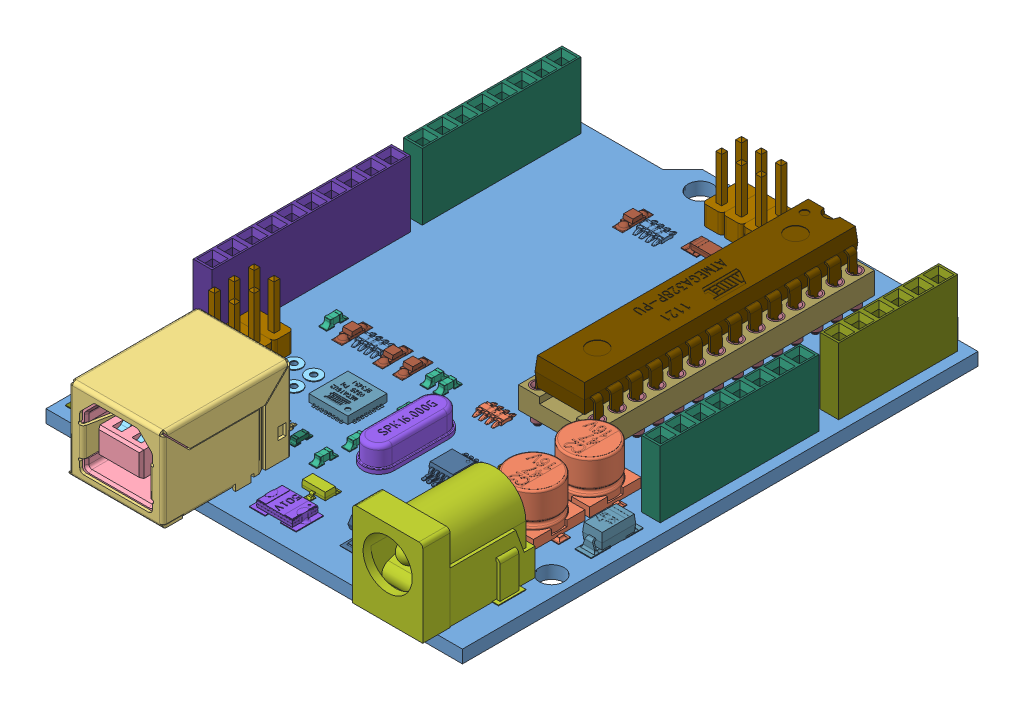
SolidWorks assembly arduino uno, configuration Default. Lengths in mm.
Overall size (53.34 15.25 74.97).
87 component instances, 35 part files, 133 mates.
Components (placement in the parent):
- unoboard blue-1: unoboard blue [Default] at origin size (53.34 1.65 68.58)
- 47uf CAP Dcase-1: 47uf CAP Dcase [Default] at (-9.4141 0 -18.4991) x (0 0 -1) z (1 0 0) size (6.6 5.81 8)
- USB type b-1: USB type b [Default] at (-38.02 0.43 6.35) size (14.34 15.2 16.54)
  - USB SHELL-1: USB SHELL [Default] at origin size (14.34 15.2 16.54)
  - USB core-1: USB core [Default] at origin size (11.3 10.68 15.75)
  - usb top contact-1: usb top contact [Default] at (1.25 6.09 -0.38) size (1 9.67 13.76)
  - usb btm contact-1: usb btm contact [Default] at (1.25 4.41 -0.38) size (1 6.84 11.76)
  - usb btm contact-2: usb btm contact [Default] at (-1.25 4.41 -0.38) size (1 6.84 11.76)
  - usb top contact-2: usb top contact [Default] at (-1.25 6.09 -0.38) size (1 9.67 13.76)
- power jack-1: power jack [Default] at (-7.675 0 1.905) size (11.2 15.2 15.9)
- 47uf CAP Dcase-2: 47uf CAP Dcase [Default] at (-9.4141 0 -25.7132) x (0 0 -1) z (1 0 0) size (6.6 5.81 8)
- crystal-1: crystal [Default] at (-26.162 0 -18.923) x (1 0 0) z (0 0 -1) size (4 5 11)
- 2pin_header__02-1: 2pin_header__02 [Default] at (-46.23 0 -15.75) size (5 11.75 2.54)
- nano - reg-1: nano - reg [Default] at (-17.399 0 -7.747) size (6.5 1.69 8.3)
- led-1: led [Default] at (-34.29 0 -27.94) x (0 0 1) z (-1 0 0) size (4 0.86 1.35)
- 2pin_header__02-2: 2pin_header__02 [Default] at (-30.43 0 -64.91) x (0 0 1) z (-1 0 0) size (5 11.75 2.54)
- dip28-1: dip28 [Default] at (-16.383 1.5 -46.355) x (0 0 -1) z (1 0 0) size (35.48 7.37 10.1)
  - dip28-1: dip28 [Default] at origin size (35.48 2.8 10.1)
  - dip socket pin-1: dip socket pin [Default] at (16.51 2.8 -3.81) size (1.7 7.37 1.7)
  - dip socket pin-2: dip socket pin [Default] at (16.51 2.8 3.81) size (1.7 7.37 1.7)
  - dip socket pin-3: dip socket pin [Default] at (13.97 2.8 -3.81) size (1.7 7.37 1.7)
  - dip socket pin-4: dip socket pin [Default] at (13.97 2.8 3.81) size (1.7 7.37 1.7)
  - dip socket pin-5: dip socket pin [Default] at (11.43 2.8 -3.81) size (1.7 7.37 1.7)
  - dip socket pin-6: dip socket pin [Default] at (11.43 2.8 3.81) size (1.7 7.37 1.7)
  - dip socket pin-7: dip socket pin [Default] at (8.89 2.8 -3.81) size (1.7 7.37 1.7)
  - dip socket pin-8: dip socket pin [Default] at (8.89 2.8 3.81) size (1.7 7.37 1.7)
  - dip socket pin-9: dip socket pin [Default] at (6.35 2.8 -3.81) size (1.7 7.37 1.7)
  - dip socket pin-10: dip socket pin [Default] at (6.35 2.8 3.81) size (1.7 7.37 1.7)
  - dip socket pin-11: dip socket pin [Default] at (3.81 2.8 -3.81) size (1.7 7.37 1.7)
  - dip socket pin-12: dip socket pin [Default] at (3.81 2.8 3.81) size (1.7 7.37 1.7)
  - dip socket pin-13: dip socket pin [Default] at (1.27 2.8 -3.81) size (1.7 7.37 1.7)
  - dip socket pin-14: dip socket pin [Default] at (1.27 2.8 3.81) size (1.7 7.37 1.7)
  - dip socket pin-15: dip socket pin [Default] at (-1.27 2.8 -3.81) size (1.7 7.37 1.7)
  - dip socket pin-16: dip socket pin [Default] at (-1.27 2.8 3.81) size (1.7 7.37 1.7)
  - dip socket pin-17: dip socket pin [Default] at (-3.81 2.8 -3.81) size (1.7 7.37 1.7)
  - dip socket pin-18: dip socket pin [Default] at (-3.81 2.8 3.81) size (1.7 7.37 1.7)
  - dip socket pin-19: dip socket pin [Default] at (-6.35 2.8 -3.81) size (1.7 7.37 1.7)
  - dip socket pin-20: dip socket pin [Default] at (-6.35 2.8 3.81) size (1.7 7.37 1.7)
  - dip socket pin-21: dip socket pin [Default] at (-8.89 2.8 -3.81) size (1.7 7.37 1.7)
  - dip socket pin-22: dip socket pin [Default] at (-8.89 2.8 3.81) size (1.7 7.37 1.7)
  - dip socket pin-23: dip socket pin [Default] at (-11.43 2.8 -3.81) size (1.7 7.37 1.7)
  - dip socket pin-24: dip socket pin [Default] at (-11.43 2.8 3.81) size (1.7 7.37 1.7)
  - dip socket pin-25: dip socket pin [Default] at (-13.97 2.8 -3.81) size (1.7 7.37 1.7)
  - dip socket pin-26: dip socket pin [Default] at (-13.97 2.8 3.81) size (1.7 7.37 1.7)
  - dip socket pin-27: dip socket pin [Default] at (-16.51 2.8 -3.81) size (1.7 7.37 1.7)
  - dip socket pin-28: dip socket pin [Default] at (-16.51 2.8 3.81) size (1.7 7.37 1.7)
- 2pin_header__02-3: 2pin_header__02 [Default] at (-27.89 0 -64.91) x (0 0 1) z (-1 0 0) size (5 11.75 2.54)
- 2pin_header__02-4: 2pin_header__02 [Default] at (-25.35 0 -64.91) x (0 0 1) z (-1 0 0) size (5 11.75 2.54)
- 2pin_header__02-5: 2pin_header__02 [Default] at (-46.23 0 -18.29) size (5 11.75 2.54)
- 2pin_header__02-6: 2pin_header__02 [Default] at (-46.23 0 -20.83) size (5 11.75 2.54)
- atmega16u2-1: atmega16u2 [Default] at (-34.671 0.06 -20) x (1 0 0) z (0 0 -1) size (5.5 1.01 5.5)
- led-2: led [Default] at (-36.83 0 -27.94) x (0 0 1) z (-1 0 0) size (4 0.86 1.35)
- led-3: led [Default] at (-42.037 0 -27.94) x (0 0 1) z (-1 0 0) size (4 0.86 1.35)
- led-4: led [Default] at (-36.576 0 -58.42) x (0 0 1) z (-1 0 0) size (4 0.86 1.35)
- 8 PORT HEADER-3: 8 PORT HEADER [Default] at (-50.8 0 -45.72) x (0 0 -1) z (1 0 0) size (20.32 10.51 2.41)
- 8 PORT HEADER-4: 8 PORT HEADER [Default] at (-2.54 0 -27.94) x (0 0 -1) z (1 0 0) size (20.32 10.51 2.41)
- 6 PORT HEADER-3: 6 PORT HEADER [Default] at (-2.54 0 -50.8) x (0 0 -1) z (1 0 0) size (15.24 10.51 2.41)
- 10 PORT HEADER-1: 10 PORT HEADER [Default] at (-50.8 0 -18.796) x (0 0 -1) z (1 0 0) size (25.4 10.51 2.41)
- ATMEL328P-1: ATMEL328P [Default] at (-16.383 4.3 -46.355) x (0 0 -1) z (1 0 0) size (35 7.27 7.87)
- 102 RESISTOR PACK-1: 102 RESISTOR PACK [Default] at (-33.782 0 -58.42) size (3.2 0.46 3)
- 102 RESISTOR PACK-2: 102 RESISTOR PACK [Default] at (-39.37 0 -27.94) size (3.2 0.46 3)
- 103 RESISTOR PACK-3: 103 RESISTOR PACK [Default] at (-23.876 0 -27.94) size (3.2 0.46 3)
- 220 RESISTOR PACK-1: 220 RESISTOR PACK [Default] at (-36.83 0 -12.827) size (3.2 0.46 3)
- 16mhz crystal - measured-1: 16mhz crystal - measured [Default] at (-24.892 0 -41.275) x (0 0 -1) z (1 0 0) size (3.4 0.8 2)
- PADS001-1: PADS001 [Default] at (-39.878 0.1 -18.288) x (-1 0 0) z (0 0 1) size (4.54 0.1 4.54)
- 603 cap on pad-1: 603 cap on pad [Default] at (-44.45 0 -27.94) x (0 0 -1) z (1 0 0) size (2.76 0.9 1.12)
- ssot3-1: ssot3 [Default] at (-26.5 0 -8.128) x (-1 0 0) z (0 0 -1) size (3 1.13 3.09)
- mf-msmf050-2-1: mf-msmf050-2 [Default] at (-26.5 0 -4.064) size (5.77 1.02 3.72)
- 603 cap on pad-2: 603 cap on pad [Default] at (-29.845 0 -27.94) x (0 0 -1) z (1 0 0) size (2.76 0.9 1.12)
- 603 cap on pad-3: 603 cap on pad [Default] at (-31.496 0 -27.94) x (0 0 -1) z (1 0 0) size (2.76 0.9 1.12)
- lmv358-1: lmv358 [Default] at (-15.24 0 -21.971) x (0 0 -1) z (1 0 0) size (3.7 1.4 2.9)
- 603 cap on pad-4: 603 cap on pad [Default] at (-15.24 0 -18.415) size (2.76 0.9 1.12)
- 603 cap on pad-5: 603 cap on pad [Default] at (-29.845 0 -12.065) x (0 0 1) z (-1 0 0) size (2.76 0.9 1.12)
- 603 cap on pad-6: 603 cap on pad [Default] at (-29.591 0 -22.352) x (0 0 1) z (-1 0 0) size (2.76 0.9 1.12)
- 603 cap on pad-7: 603 cap on pad [Default] at (-29.591 0 -16.002) x (0 0 1) z (-1 0 0) size (2.76 0.9 1.12)
- 603 cap on pad-8: 603 cap on pad [Default] at (-41.91 0 -12.7) x (0 0 1) z (-1 0 0) size (2.76 0.9 1.12)
- lp2985dgkr-1: lp2985dgkr [Default] at (-20.32 0 -19.05) x (0 0 -1) z (1 0 0) size (5.85 1.1 3)
- cd1206 diode-1: cd1206 diode [Default] at (-27.94 0 -59.436) x (0 0 -1) z (1 0 0) size (2.07 0.96 5)
- cd1206 diode-2: cd1206 diode [Default] at (-46.228 0 -13.081) x (0 0 1) z (-1 0 0) size (2.07 0.96 5)
- 603 resistor-1: 603 resistor [Default] at (-29.591 0 -19.05) x (0 0 1) z (-1 0 0) size (2.36 0.61 1.03)
- blm21-1: blm21 [Default] at (-45.085 0 -7.62) x (0 0 -1) z (1 0 0) size (2.76 0.95 1.32)
- m7 diode-1: m7 diode [Default] at (-2.794 0 -21.59) x (0 0 -1) z (1 0 0) size (6.66 2.35 2.5)
- MLC0603-1: MLC0603 [Default] at (-33.655 0 -12.827) x (0 0 -1) z (1 0 0) size (2.36 0.6 1.03)
- MLC0603-2: MLC0603 [Default] at (-39.37 0 -12.827) x (0 0 -1) z (1 0 0) size (2.36 0.6 1.03)
- RESET BUTTON-1: RESET BUTTON [Default] at (-49.403 0 -6.35) size (6.2 3.1 9.6)
  - RESET CORE-1: RESET CORE [Default] at (0 0.1 0) x (-1 0 0) z (0 0 -1) size (6.2 3.1 9.6)
  - RESET-1: RESET [Default] at (0 0.1 0) x (0 0 1) z (-1 0 0) size (7.3 2 6.2)
Mates (geometry in assembly coordinates):
- Distance1: distance = 1.905 mm: plane of power jack-1 through (-7.675 0 1.905) normal (0 0 1); plane of unoboard blue-1 through (0 0 0) normal (0 0 1)
- Coincident2: coincident: plane of unoboard blue-1 through (0 0 0) normal (0 1 0); plane of power jack-1 through (-7.675 0 1.905) normal (0 1 0)
- Coincident3: coincident: plane of unoboard blue-1 through (0 0 0) normal (0 1 0); plane of USB type b-1/USB core-1 through (-38.02 0 6.35) normal (0 -1 0)
- Distance2: distance = 6.35 mm: plane of USB type b-1/USB SHELL-1 through (-38.02 0.43 6.35) normal (0 0 1); plane of unoboard blue-1 through (0 0 0) normal (0 0 1)
- Coincident5: coincident: plane of unoboard blue-1 through (0 0 0) normal (0 1 0); plane of 47uf CAP Dcase-1 through (-9.4141 0 -18.4991) normal (0 1 0)
- Parallel1: parallel: plane of unoboard blue-1 through (0 0 0) normal (0 0 1); plane of 47uf CAP Dcase-1 through (-9.4141 0 -18.4991) normal (0 0 -1)
- Coincident7: coincident: plane of 47uf CAP Dcase-1 through (-6.1141 1.5 -15.1991) normal (1 0 0); plane of 47uf CAP Dcase-2 through (-6.1141 1.5 -22.4132) normal (1 0 0)
- Coincident8: coincident: plane of unoboard blue-1 through (0 0 0) normal (0 1 0); plane of 47uf CAP Dcase-2 through (-8.1891 0 -25.7132) normal (0 -1 0)
- Distance3: distance = 3.175 mm: plane of power jack-1 through (-3.175 10.5 -1.595) normal (1 0 0); plane of unoboard blue-1 through (0 -1.65 0) normal (1 0 0)
- Distance4: distance = 32 mm: plane of USB type b-1/USB SHELL-1 through (-32 0.43 6.35) normal (1 0 0); plane of unoboard blue-1 through (0 -1.65 0) normal (1 0 0)
- Coincident11: coincident: plane of unoboard blue-1 through (0 0 0) normal (0 1 0); plane of crystal-1 through (-26.162 0 -22.423) normal (0 -1 0)
- Concentric1: concentric: cylinder of unoboard blue-1 through (-26.162 -10 -16.383) axis (0 1 0) radius 0.5; cylinder of crystal-1 through (-26.162 -2 -16.383) axis (0 1 0) radius 0.4
- Concentric2: concentric: cylinder of unoboard blue-1 through (-26.162 -10 -21.463) axis (0 1 0) radius 0.5; cylinder of crystal-1 through (-26.162 -2 -21.463) axis (0 1 0) radius 0.4
- Coincident12: coincident: plane of unoboard blue-1 through (0 0 0) normal (0 1 0); plane of 2pin_header__02-1 through (-44.23 0 -14.98) normal (0 -1 0)
- Distance5: distance = 15.75 mm: plane of 2pin_header__02-1 through (-46.23 0 -15.75) normal (0 0 1); plane of assembly through (0 0 0) normal (0 0 1)
- Distance6: distance = 46.23 mm: plane of 2pin_header__02-1 through (-46.23 0 -15.75) normal (1 0 0); plane of assembly through (0 0 0) normal (1 0 0)
- Coincident15: coincident: plane of unoboard blue-1 through (0 0 0) normal (0 1 0); plane of 2pin_header__02-2 through (-31.2 0 -62.91) normal (0 -1 0)
- Distance7: distance = 64.91 mm: plane of 2pin_header__02-2 through (-30.43 0 -64.91) normal (0 0 1); plane of assembly through (0 0 0) normal (0 0 1)
- Distance8: distance = 30.43 mm: plane of 2pin_header__02-2 through (-30.43 0 -64.91) normal (-1 0 0); plane of assembly through (0 0 0) normal (1 0 0)
- Coincident19: coincident: plane of unoboard blue-1 through (0 0 0) normal (0 1 0); plane of nano - reg-1 through (-17.399 0 -7.747) normal (0 -1 0)
- Concentric3: concentric: cylinder of unoboard blue-1 through (-20.193 -10 -62.865) axis (0 1 0) radius 0.4; cylinder of dip28-1/dip socket pin-1 through (-20.193 33.2926 -62.865) axis (0 1 0) radius 0.25
- Concentric4: concentric: cylinder of unoboard blue-1 through (-12.573 -10 -29.845) axis (0 1 0) radius 0.4; cylinder of dip28-1/dip socket pin-28 through (-12.573 33.2926 -29.845) axis (0 1 0) radius 0.25
- Distance9: distance = 1.5 mm: plane of dip28-1/dip28-1 through (-11.333 1.5 -64.095) normal (0 -1 0); plane of unoboard blue-1 through (0 0 0) normal (0 1 0)
- Coincident21: coincident: plane of unoboard blue-1 through (0 0 0) normal (0 1 0); plane of atmega16u2-1 through (-34.671 0 -20) normal (0 -1 0)
- Distance10: distance = 20 mm: plane of atmega16u2-1 through (-34.671 0.06 -20) normal (0 0 -1); plane of unoboard blue-1 through (0 0 0) normal (0 0 1)
- Distance11: distance = 34.671 mm: plane of atmega16u2-1 through (-34.671 0.06 -20) normal (1 0 0); plane of unoboard blue-1 through (0 0 0) normal (1 0 0)
- Coincident25: coincident: plane of unoboard blue-1 through (0 0 0) normal (0 1 0); plane of led-1 through (-34.29 0 -28.94) normal (0 -1 0)
- Distance12: distance = 34.29 mm: plane of led-1 through (-34.29 0 -27.94) normal (-1 0 0); plane of unoboard blue-1 through (0 0 0) normal (1 0 0)
- Distance13: distance = 27.94 mm: plane of led-1 through (-34.29 0 -27.94) normal (0 0 1); plane of unoboard blue-1 through (0 0 0) normal (0 0 1)
- Coincident28: coincident: plane of led-2 through (-36.83 0 -28.94) normal (0 -1 0); plane of led-3 through (-42.037 0 -28.94) normal (0 -1 0)
- Coincident29: coincident: plane of led-1 through (-34.29 0 -27.94) normal (0 0 1); plane of led-2 through (-36.83 0 -27.94) normal (0 0 1)
- Coincident30: coincident: plane of led-1 through (-34.29 0 -27.94) normal (0 0 1); plane of led-3 through (-42.037 0 -27.94) normal (0 0 1)
- Distance14: distance = 2.54 mm: plane of led-2 through (-36.83 0 -27.94) normal (-1 0 0); plane of led-1 through (-34.29 0 -27.94) normal (-1 0 0)
- Coincident32: coincident: plane of unoboard blue-1 through (0 0 0) normal (0 1 0); plane of led-2 through (-36.83 0 -28.94) normal (0 -1 0)
- Distance15: distance = 42.037 mm: plane of led-3 through (-42.037 0 -27.94) normal (-1 0 0); plane of unoboard blue-1 through (0 0 0) normal (1 0 0)
- Coincident34: coincident: plane of unoboard blue-1 through (0 0 0) normal (0 1 0); plane of led-4 through (-36.576 0 -59.42) normal (0 -1 0)
- Distance16: distance = 36.576 mm: plane of led-4 through (-36.576 0 -58.42) normal (-1 0 0); plane of unoboard blue-1 through (0 0 0) normal (1 0 0)
- Distance17: distance = 58.42 mm: plane of led-4 through (-36.576 0 -58.42) normal (0 0 1); plane of unoboard blue-1 through (0 0 0) normal (0 0 1)
- Coincident37: coincident: plane of unoboard blue-1 through (0 0 0) normal (0 1 0); plane of 8 PORT HEADER-4 through (-2.54 0 -27.94) normal (0 1 0)
- Coincident38: coincident: plane of unoboard blue-1 through (0 0 0) normal (0 1 0); plane of 8 PORT HEADER-3 through (-50.8 0 -45.72) normal (0 1 0)
- Parallel2: parallel: plane of unoboard blue-1 through (0 0 0) normal (1 0 0); plane of 8 PORT HEADER-4 through (-2.54 0 -27.94) normal (1 0 0)
- Parallel3: parallel: plane of unoboard blue-1 through (0 0 0) normal (1 0 0); plane of 8 PORT HEADER-3 through (-50.8 0 -45.72) normal (1 0 0)
- Concentric5: concentric: cylinder of unoboard blue-1 through (-2.54 -1.65 -27.94) axis (0 1 0) radius 0.4; line of 8 PORT HEADER-4 through (-2.54 -2.5255 -27.94) axis (0 1 0)
- Concentric6: concentric: cylinder of unoboard blue-1 through (-50.8 -1.65 -45.72) axis (0 1 0) radius 0.4; line of 8 PORT HEADER-3 through (-50.8 -2.5255 -45.72) axis (0 1 0)
- Coincident43: coincident: plane of unoboard blue-1 through (0 0 0) normal (0 1 0); plane of 10 PORT HEADER-1 through (-50.8 0 -18.796) normal (0 1 0)
- Coincident44: coincident: plane of unoboard blue-1 through (0 0 0) normal (0 1 0); plane of 6 PORT HEADER-3 through (-2.54 0 -50.8) normal (0 1 0)
- Parallel4: parallel: plane of unoboard blue-1 through (0 0 0) normal (1 0 0); plane of 6 PORT HEADER-3 through (-2.54 0 -50.8) normal (1 0 0)
- Parallel5: parallel: plane of unoboard blue-1 through (0 0 0) normal (1 0 0); plane of 10 PORT HEADER-1 through (-50.8 0 -18.796) normal (1 0 0)
- Concentric7: concentric: cylinder of unoboard blue-1 through (-50.8 -1.65 -18.796) axis (0 1 0) radius 0.4; line of 10 PORT HEADER-1 through (-50.8 -2.5255 -18.796) axis (0 1 0)
- Concentric9: concentric: cylinder of unoboard blue-1 through (-2.54 -1.65 -50.8) axis (0 1 0) radius 0.4; line of 6 PORT HEADER-3 through (-2.54 -2.5255 -50.8) axis (0 1 0)
- Coincident50: coincident: plane of dip28-1/dip28-1 through (-16.383 1.5 -46.355) normal (0 0 -1); plane of ATMEL328P-1 through (-16.383 4.3 -46.355) normal (0 0 -1)
- Coincident51: coincident: plane of dip28-1/dip28-1 through (-16.383 1.5 -46.355) normal (1 0 0); plane of ATMEL328P-1 through (-16.383 4.3 -46.355) normal (1 0 0)
- Coincident52: coincident: plane of dip28-1/dip28-1 through (-11.333 4.3 -64.095) normal (0 1 0); plane of ATMEL328P-1 through (-16.383 4.3 -46.355) normal (0 1 0)
- Distance18: distance = 7.747 mm: plane of nano - reg-1 through (-17.399 0 -7.747) normal (0 0 1); line of unoboard blue-1 through (-53.34 0 0) axis (1 0 0)
- Distance19: distance = 17.399 mm: plane of nano - reg-1 through (-17.399 0 -7.747) normal (1 0 0); plane of unoboard blue-1 through (0 0 0) normal (1 0 0)
- Coincident55: coincident: plane of unoboard blue-1 through (0 0 0) normal (0 1 0); plane of 102 RESISTOR PACK-1 through (-33.982 0 -59.12) normal (0 -1 0)
- Distance20: distance = 33.782 mm: plane of 102 RESISTOR PACK-1 through (-33.782 0 -58.42) normal (1 0 0); plane of unoboard blue-1 through (0 0 0) normal (1 0 0)
- Distance21: distance = 58.42 mm: plane of 102 RESISTOR PACK-1 through (-33.782 0 -58.42) normal (0 0 1); plane of unoboard blue-1 through (0 0 0) normal (0 0 1)
- Coincident58: coincident: plane of 102 RESISTOR PACK-2 through (-39.37 0 -27.94) normal (0 1 0); plane of 103 RESISTOR PACK-3 through (-23.876 0 -27.94) normal (0 1 0)
- Coincident59: coincident: plane of unoboard blue-1 through (0 0 0) normal (0 1 0); plane of 103 RESISTOR PACK-3 through (-23.876 0 -27.94) normal (0 1 0)
- Coincident60: coincident: plane of 102 RESISTOR PACK-2 through (-39.37 0 -27.94) normal (0 0 1); plane of 103 RESISTOR PACK-3 through (-23.876 0 -27.94) normal (0 0 1)
- Distance22: distance = 23.876 mm: plane of 103 RESISTOR PACK-3 through (-23.876 0 -27.94) normal (1 0 0); plane of unoboard blue-1 through (0 0 0) normal (1 0 0)
- Distance23: distance = 39.37 mm: plane of 102 RESISTOR PACK-2 through (-39.37 0 -27.94) normal (1 0 0); plane of unoboard blue-1 through (0 0 0) normal (1 0 0)
- Distance24: distance = 27.94 mm: plane of 102 RESISTOR PACK-2 through (-39.37 0 -27.94) normal (0 0 1); plane of unoboard blue-1 through (0 0 0) normal (0 0 1)
- Distance25: distance = 12.827 mm: plane of 220 RESISTOR PACK-1 through (-36.83 0 -12.827) normal (0 0 1); plane of unoboard blue-1 through (0 0 0) normal (0 0 1)
- Distance26: distance = 36.83 mm: plane of 220 RESISTOR PACK-1 through (-36.83 0 -12.827) normal (1 0 0); plane of unoboard blue-1 through (0 0 0) normal (1 0 0)
- Coincident66: coincident: plane of unoboard blue-1 through (0 0 0) normal (0 1 0); plane of 220 RESISTOR PACK-1 through (-36.83 0 -12.827) normal (0 1 0)
- Coincident67: coincident: plane of unoboard blue-1 through (0 0 0) normal (0 1 0); plane of 16mhz crystal - measured-1 through (-24.892 0 -41.275) normal (0 -1 0)
- Distance27: distance = 41.275 mm: plane of 16mhz crystal - measured-1 through (-24.892 0 -41.275) normal (0 0 -1); plane of unoboard blue-1 through (0 0 0) normal (0 0 1)
- Distance28: distance = 24.892 mm: plane of 16mhz crystal - measured-1 through (-24.892 0 -41.275) normal (1 0 0); plane of unoboard blue-1 through (0 0 0) normal (1 0 0)
- Coincident70: coincident: plane of unoboard blue-1 through (0 0 0) normal (0 1 0); plane of PADS001-1 through (-42.418 0 -18.288) normal (0 -1 0)
- Distance29: distance = 18.288 mm: plane of PADS001-1 through (-39.878 0.1 -18.288) normal (0 0 1); plane of unoboard blue-1 through (0 0 0) normal (0 0 1)
- Distance30: distance = 39.878 mm: plane of PADS001-1 through (-39.878 0.1 -18.288) normal (-1 0 0); plane of unoboard blue-1 through (0 0 0) normal (1 0 0)
- Distance31: distance = 4.064 mm: plane of mf-msmf050-2-1 through (-26.5 0 -4.064) normal (0 0 1); plane of unoboard blue-1 through (0 0 0) normal (0 0 1)
- Distance32: distance = 26.5 mm: plane of mf-msmf050-2-1 through (-26.5 0 -4.064) normal (1 0 0); plane of unoboard blue-1 through (0 0 0) normal (1 0 0)
- Coincident72: coincident: plane of unoboard blue-1 through (0 0 0) normal (0 1 0); plane of mf-msmf050-2-1 through (-26.5 0 -4.064) normal (0 1 0)
- Distance33: distance = 8.128 mm: plane of unoboard blue-1 through (0 0 0) normal (0 0 1); plane of ssot3-1 through (-26.5 0 -8.128) normal (0 0 -1)
- Coincident74: coincident: plane of ssot3-1 through (-26.5 0 -8.128) normal (-1 0 0); plane of mf-msmf050-2-1 through (-26.5 0 -4.064) normal (1 0 0)
- Coincident75: coincident: plane of unoboard blue-1 through (0 0 0) normal (0 1 0); plane of ssot3-1 through (-26.5 0 -8.128) normal (0 1 0)
- Coincident76: coincident: plane of led-1 through (-34.29 0 -27.94) normal (0 0 1); plane of 603 cap on pad-1 through (-44.45 0 -27.94) normal (0 0 -1)
- Coincident77: coincident: plane of unoboard blue-1 through (0 0 0) normal (0 1 0); plane of 603 cap on pad-1 through (-44.45 0 -27.94) normal (0 1 0)
- Distance34: distance = 44.45 mm: plane of 603 cap on pad-1 through (-44.45 0 -27.94) normal (1 0 0); plane of unoboard blue-1 through (0 0 0) normal (1 0 0)
- Coincident79: coincident: plane of 603 cap on pad-2 through (-29.845 0 -27.94) normal (0 1 0); plane of 603 cap on pad-3 through (-31.496 0 -27.94) normal (0 1 0)
- Coincident80: coincident: plane of 603 cap on pad-2 through (-29.845 0 -27.94) normal (0 0 -1); plane of 603 cap on pad-3 through (-31.496 0 -27.94) normal (0 0 -1)
- Coincident81: coincident: plane of unoboard blue-1 through (0 0 0) normal (0 1 0); plane of 603 cap on pad-2 through (-29.845 0 -27.94) normal (0 1 0)
- Coincident82: coincident: plane of 603 cap on pad-1 through (-44.45 0 -27.94) normal (0 0 -1); plane of 603 cap on pad-2 through (-29.845 0 -27.94) normal (0 0 -1)
- Distance36: distance = 29.845 mm: plane of 603 cap on pad-2 through (-29.845 0 -27.94) normal (1 0 0); plane of unoboard blue-1 through (0 0 0) normal (1 0 0)
- Distance37: distance = 31.496 mm: plane of 603 cap on pad-3 through (-31.496 0 -27.94) normal (1 0 0); plane of unoboard blue-1 through (0 0 0) normal (1 0 0)
- Distance38: distance = 15.24 mm: plane of unoboard blue-1 through (0 0 0) normal (1 0 0); plane of lmv358-1 through (-15.24 0 -21.971) normal (1 0 0)
- Distance39: distance = 21.971 mm: plane of lmv358-1 through (-15.24 0 -21.971) normal (0 0 -1); plane of unoboard blue-1 through (0 0 0) normal (0 0 1)
- Coincident88: coincident: plane of unoboard blue-1 through (0 0 0) normal (0 1 0); plane of lmv358-1 through (-15.24 0 -21.971) normal (0 1 0)
- Distance40: distance = 18.415 mm: plane of 603 cap on pad-4 through (-15.24 0 -18.415) normal (0 0 1); plane of unoboard blue-1 through (0 0 0) normal (0 0 1)
- Distance41: distance = 15.24 mm: plane of 603 cap on pad-4 through (-15.24 0 -18.415) normal (1 0 0); plane of unoboard blue-1 through (0 0 0) normal (1 0 0)
- Coincident91: coincident: plane of unoboard blue-1 through (0 0 0) normal (0 1 0); plane of 603 cap on pad-4 through (-15.24 0 -18.415) normal (0 1 0)
- Coincident92: coincident: plane of unoboard blue-1 through (0 0 0) normal (0 1 0); plane of 603 cap on pad-7 through (-29.591 0 -16.002) normal (0 1 0)
- Coincident93: coincident: plane of unoboard blue-1 through (0 0 0) normal (0 1 0); plane of 603 cap on pad-6 through (-29.591 0 -22.352) normal (0 1 0)
- Coincident94: coincident: plane of 603 cap on pad-5 through (-29.845 0 -12.065) normal (0 1 0); plane of unoboard blue-1 through (0 0 0) normal (0 1 0)
- Coincident95: coincident: plane of 603 cap on pad-8 through (-41.91 0 -12.7) normal (0 1 0); plane of unoboard blue-1 through (0 0 0) normal (0 1 0)
- Coincident96: coincident: plane of 603 cap on pad-7 through (-29.591 0 -16.002) normal (-1 0 0); plane of 603 cap on pad-6 through (-29.591 0 -22.352) normal (-1 0 0)
- Distance42: distance = 29.591 mm: plane of 603 cap on pad-7 through (-29.591 0 -16.002) normal (-1 0 0); plane of unoboard blue-1 through (0 0 0) normal (1 0 0)
- Distance43: distance = 22.352 mm: plane of 603 cap on pad-6 through (-29.591 0 -22.352) normal (0 0 1); line of unoboard blue-1 through (-53.34 0 0) axis (1 0 0)
- Distance44: distance = 16.002 mm: plane of 603 cap on pad-7 through (-29.591 0 -16.002) normal (0 0 1); plane of unoboard blue-1 through (0 0 0) normal (0 0 1)
- Distance45: distance = 29.845 mm: plane of 603 cap on pad-5 through (-29.845 0 -12.065) normal (-1 0 0); plane of unoboard blue-1 through (0 0 0) normal (1 0 0)
- Distance46: distance = 12.065 mm: plane of 603 cap on pad-5 through (-29.845 0 -12.065) normal (0 0 1); plane of unoboard blue-1 through (0 0 0) normal (0 0 1)
- Distance47: distance = 41.91 mm: plane of 603 cap on pad-8 through (-41.91 0 -12.7) normal (-1 0 0); plane of unoboard blue-1 through (0 0 0) normal (1 0 0)
- Distance48: distance = 12.7 mm: plane of 603 cap on pad-8 through (-41.91 0 -12.7) normal (0 0 1); plane of unoboard blue-1 through (0 0 0) normal (0 0 1)
- Distance49: distance = 20.32 mm: plane of lp2985dgkr-1 through (-20.32 0 -19.05) normal (1 0 0); plane of unoboard blue-1 through (0 0 0) normal (1 0 0)
- Distance50: distance = 19.05 mm: plane of lp2985dgkr-1 through (-20.32 0 -19.05) normal (0 0 -1); plane of unoboard blue-1 through (0 0 0) normal (0 0 1)
- Coincident99: coincident: plane of unoboard blue-1 through (0 0 0) normal (0 1 0); plane of lp2985dgkr-1 through (-20.32 0 -19.05) normal (0 1 0)
- Distance51: distance = 27.94 mm: plane of cd1206 diode-1 through (-27.94 0 -59.436) normal (1 0 0); plane of unoboard blue-1 through (0 0 0) normal (1 0 0)
- Distance52: distance = 59.436 mm: plane of cd1206 diode-1 through (-27.94 0 -59.436) normal (0 0 -1); plane of unoboard blue-1 through (0 0 0) normal (0 0 1)
- Coincident102: coincident: plane of unoboard blue-1 through (0 0 0) normal (0 1 0); plane of cd1206 diode-1 through (-27.94 0 -59.436) normal (0 1 0)
- Distance53: distance = 46.228 mm: plane of cd1206 diode-2 through (-46.228 0 -13.081) normal (-1 0 0); plane of unoboard blue-1 through (0 0 0) normal (1 0 0)
- Distance54: distance = 13.081 mm: plane of unoboard blue-1 through (0 0 0) normal (0 0 1); plane of cd1206 diode-2 through (-46.228 0 -13.081) normal (0 0 1)
- Coincident105: coincident: plane of unoboard blue-1 through (0 0 0) normal (0 1 0); plane of cd1206 diode-2 through (-46.228 0 -13.081) normal (0 1 0)
- Distance55: distance = 29.591 mm: plane of 603 resistor-1 through (-29.591 0 -19.05) normal (-1 0 0); plane of unoboard blue-1 through (0 0 0) normal (1 0 0)
- Distance56: distance = 19.05 mm: plane of 603 resistor-1 through (-29.591 0 -19.05) normal (0 0 1); plane of unoboard blue-1 through (0 0 0) normal (0 0 1)
- Coincident108: coincident: plane of unoboard blue-1 through (0 0 0) normal (0 1 0); plane of 603 resistor-1 through (-29.591 0 -19.05) normal (0 1 0)
- Distance57: distance = 7.62 mm: plane of blm21-1 through (-45.085 0 -7.62) normal (0 0 -1); plane of unoboard blue-1 through (0 0 0) normal (0 0 1)
- Distance58: distance = 45.085 mm: plane of blm21-1 through (-45.085 0 -7.62) normal (1 0 0); plane of unoboard blue-1 through (0 0 0) normal (1 0 0)
- Distance59: distance = 21.59 mm: plane of m7 diode-1 through (-2.794 0 -21.59) normal (0 0 -1); plane of unoboard blue-1 through (0 0 0) normal (0 0 1)
- Distance60: distance = 2.794 mm: plane of m7 diode-1 through (-2.794 0 -21.59) normal (1 0 0); plane of unoboard blue-1 through (0 0 0) normal (1 0 0)
- Coincident113: coincident: plane of unoboard blue-1 through (0 0 0) normal (0 1 0); plane of m7 diode-1 through (-2.794 0 -21.59) normal (0 1 0)
- Coincident114: coincident: plane of 220 RESISTOR PACK-1 through (-36.83 0 -12.827) normal (0 0 1); plane of MLC0603-1 through (-33.655 0 -12.827) normal (0 0 -1)
- Distance61: distance = 33.655 mm: plane of MLC0603-1 through (-33.655 0 -12.827) normal (1 0 0); plane of unoboard blue-1 through (0 0 0) normal (1 0 0)
- Coincident115: coincident: plane of unoboard blue-1 through (0 0 0) normal (0 1 0); plane of MLC0603-1 through (-33.655 0 -12.827) normal (0 1 0)
- Coincident116: coincident: plane of unoboard blue-1 through (0 0 0) normal (0 1 0); plane of blm21-1 through (-45.085 0 -7.62) normal (0 1 0)
- Coincident117: coincident: plane of 220 RESISTOR PACK-1 through (-36.83 0 -12.827) normal (0 0 1); plane of MLC0603-2 through (-39.37 0 -12.827) normal (0 0 -1)
- Coincident118: coincident: plane of unoboard blue-1 through (0 0 0) normal (0 1 0); plane of MLC0603-2 through (-39.37 0 -12.827) normal (0 1 0)
- Distance62: distance = 39.37 mm: plane of MLC0603-2 through (-39.37 0 -12.827) normal (1 0 0); plane of unoboard blue-1 through (0 0 0) normal (1 0 0)
- Distance63: distance = 49.403 mm: plane of RESET BUTTON-1 through (-49.403 0 -6.35) normal (1 0 0); plane of unoboard blue-1 through (0 0 0) normal (1 0 0)
- Distance64: distance = 6.35 mm: plane of RESET BUTTON-1; plane of unoboard blue-1 through (0 0 0) normal (0 0 1)
- Coincident122: coincident: plane of unoboard blue-1 through (0 0 0) normal (0 1 0); plane of RESET BUTTON-1 through (-49.403 0 -6.35) normal (0 1 0)
